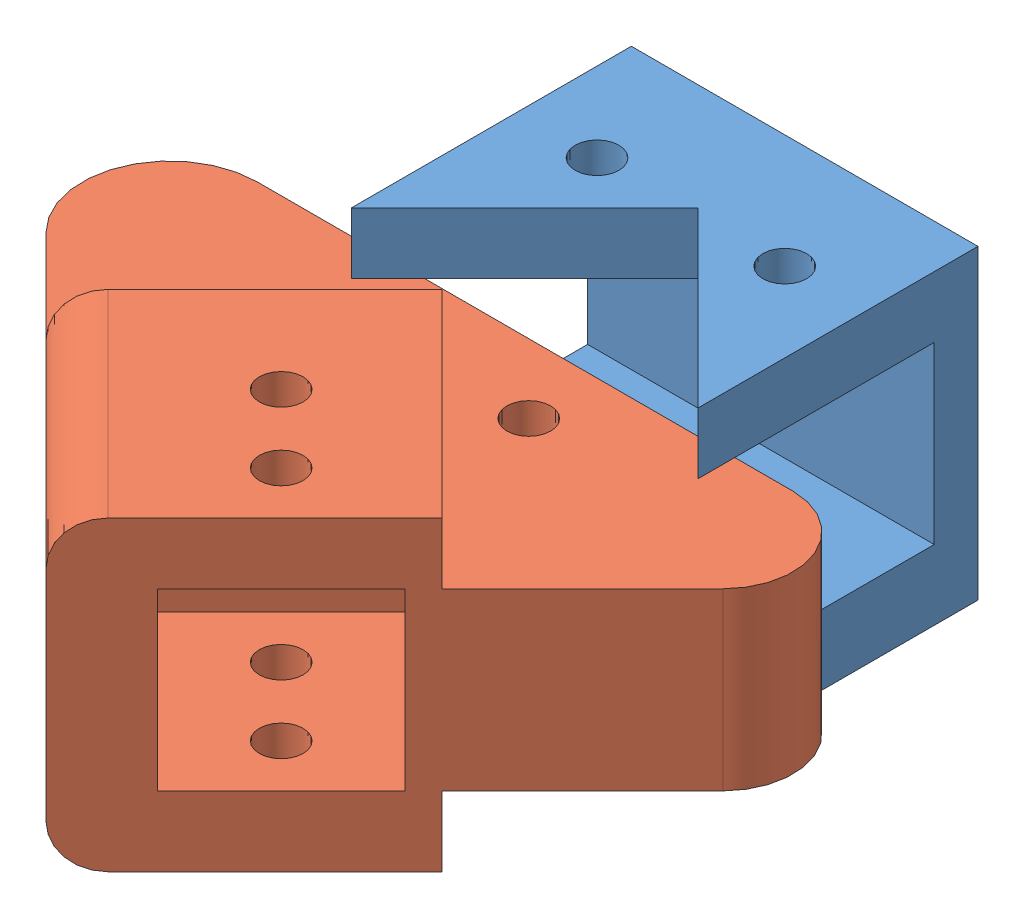
SolidWorks assembly motortutucular, configuration Varsayılan. Lengths in mm.
Overall size (86.65 35.79 86.65).
2 component instances, 2 part files, 0 mates.
Components (placement in the parent):
- motortutucuarka-1: motortutucuarka [Varsayılan] at (-25.258 -13.6326 22.249) size (39.6 35 31.98)
- motortutucuon-1: motortutucuon [Varsayılan] at (-7.807 -9.4261 70.9343) x (-0.707107 0 0.707107) z (0 1 0) size (62.69 59.86 35)
